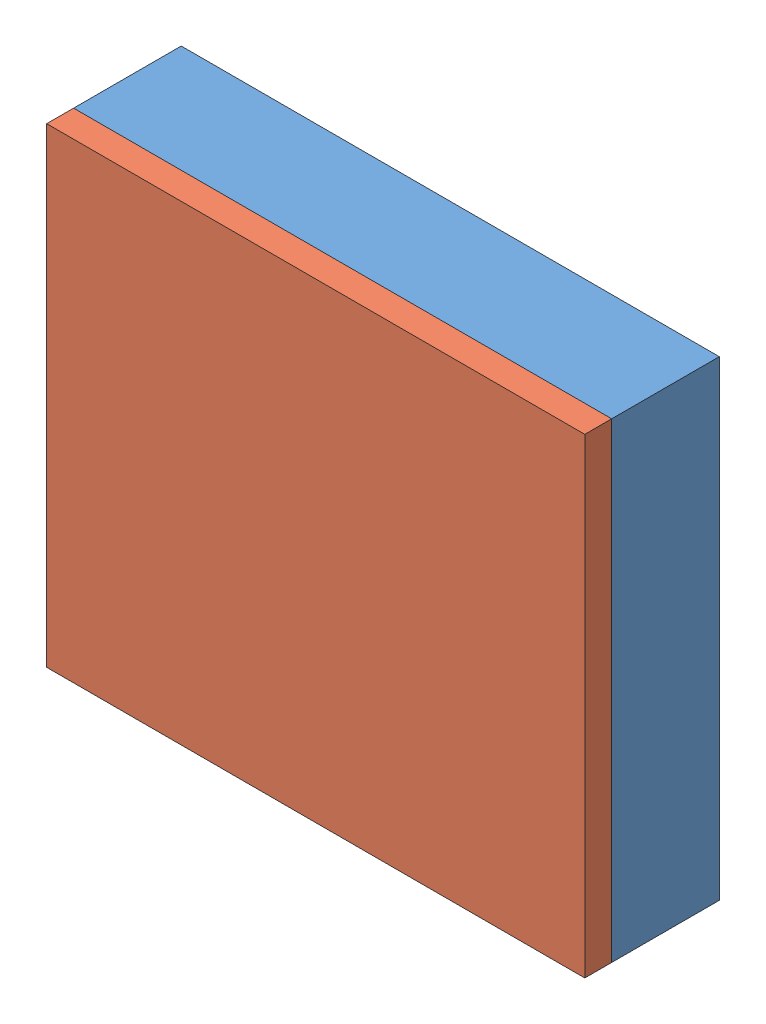
SolidWorks assembly 总装, configuration 默认. Lengths in mm.
Overall size (400 350.76 100).
4 component instances, 4 part files, 9 mates.
Components (placement in the parent):
- 主体-1: 主体 [默认] at (-113.8127 -48.9152 365) size (400 350 90)
- 盖子-1: 盖子 [默认] at (-113.8127 -48.9152 465) x (-1 0 0) z (0 0 -1) size (400 350 20)
- 抽屉-1: 抽屉 [默认] at (-113.8127 -64.6737 368) size (390 320 34)
- 颜料盒-1: 颜料盒 [默认] at (-167.8127 80.0848 405) size (260 78 50)
Mates (geometry in assembly coordinates):
- 重合2: coincident: plane of assembly; plane of assembly; plane of 主体-1 through (-313.8127 126.0848 445) normal (-1 0 0); plane of 盖子-1 through (-313.8127 126.0848 445) normal (-1 0 0)
- 重合3: coincident: line of assembly; line of assembly; line of 主体-1 through (86.1873 126.0848 445) axis (-1 0 0); line of 盖子-1 through (-313.8127 126.0848 445) axis (1 0 0)
- LimitAngle1: limit planar angle = 0 rad: plane of assembly; plane of assembly; plane of 盖子-1 through (-113.8127 -48.9152 445) normal (0 0 -1); plane of 主体-1 through (-113.8127 -48.9152 445) normal (0 0 1)
- 重合4: coincident: plane of assembly; plane of assembly; plane of 主体-1 through (-288.8127 96.0848 368) normal (0 0 1); plane of 抽屉-1 through (-113.8127 -64.6737 368) normal (0 0 -1)
- 重合5: coincident: plane of assembly; plane of assembly; plane of 主体-1 through (-288.8127 96.0848 402) normal (1 0 0); plane of 抽屉-1 through (-288.8127 95.3263 402) normal (-1 0 0)
- LimitDistance1: limit distance = 0.7585 mm: plane of assembly; plane of assembly; plane of 主体-1 through (-113.8127 96.0848 365) normal (0 -1 0); plane of 抽屉-1 through (-288.8127 95.3263 402) normal (0 1 0)
- 重合6: coincident: plane of assembly; plane of assembly; plane of 主体-1 through (-113.8127 -48.9152 405) normal (0 0 1); plane of 颜料盒-1 through (-167.8127 80.0848 405) normal (0 0 -1)
- 距离2: distance = 1 mm: plane of assembly; plane of assembly; plane of 颜料盒-1 through (-297.8127 41.0848 455) normal (0 -1 0); plane of 主体-1 through (-307.8127 40.0848 435) normal (0 1 0)
- 距离3: distance = 10 mm: plane of assembly; plane of assembly; plane of 颜料盒-1 through (-297.8127 119.0848 455) normal (-1 0 0); plane of 主体-1 through (-307.8127 120.0848 405) normal (1 0 0)
